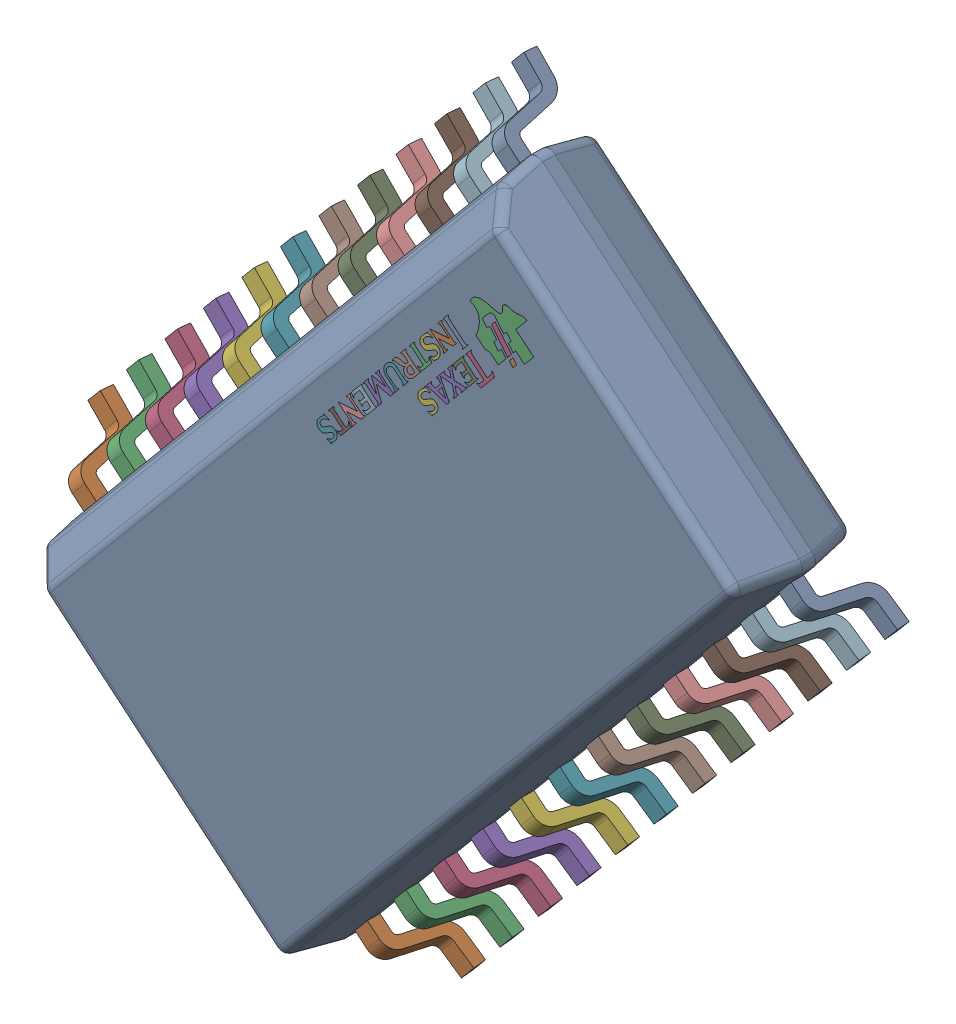
SolidWorks assembly U3, configuration Défaut. Lengths in mm.
Overall size (17.82 18.44 2.65).
28 component instances, 4 part files, 0 mates.
Components (placement in the parent):
- IC_Texas_Instruments_CD74HC4067M96_eec-1: IC_Texas_Instruments_CD74HC4067M96_eec [Défaut] at (-19.865 -20.828 0) x (-0.766044 0.642788 0) z (0 0 1) size (10.34 15.4 2.65)
  - BODY-SO-1: BODY-SO [Défaut] at (0 0 1.0825) x (0 1 0) z (1 0 0) size (15.4 2.45 7.5)
  - LEAD-SO-1: LEAD-SO [Défaut] at (4.315 6.985 0.25) x (0 1 0) z (1 0 0) size (0.41 1.43 1.42)
  - LEAD-SO-2: LEAD-SO [Défaut] at (4.315 5.715 0.25) x (0 1 0) z (1 0 0) size (0.41 1.43 1.42)
  - LEAD-SO-3: LEAD-SO [Défaut] at (4.315 4.445 0.25) x (0 1 0) z (1 0 0) size (0.41 1.43 1.42)
  - LEAD-SO-4: LEAD-SO [Défaut] at (4.315 3.175 0.25) x (0 1 0) z (1 0 0) size (0.41 1.43 1.42)
  - LEAD-SO-5: LEAD-SO [Défaut] at (4.315 1.905 0.25) x (0 1 0) z (1 0 0) size (0.41 1.43 1.42)
  - LEAD-SO-6: LEAD-SO [Défaut] at (4.315 0.635 0.25) x (0 1 0) z (1 0 0) size (0.41 1.43 1.42)
  - LEAD-SO-7: LEAD-SO [Défaut] at (4.315 -0.635 0.25) x (0 1 0) z (1 0 0) size (0.41 1.43 1.42)
  - LEAD-SO-8: LEAD-SO [Défaut] at (4.315 -1.905 0.25) x (0 1 0) z (1 0 0) size (0.41 1.43 1.42)
  - LEAD-SO-9: LEAD-SO [Défaut] at (4.315 -3.175 0.25) x (0 1 0) z (1 0 0) size (0.41 1.43 1.42)
  - LEAD-SO-10: LEAD-SO [Défaut] at (4.315 -4.445 0.25) x (0 1 0) z (1 0 0) size (0.41 1.43 1.42)
  - LEAD-SO-11: LEAD-SO [Défaut] at (4.315 -5.715 0.25) x (0 1 0) z (1 0 0) size (0.41 1.43 1.42)
  - LEAD-SO-12: LEAD-SO [Défaut] at (4.315 -6.985 0.25) x (0 1 0) z (1 0 0) size (0.41 1.43 1.42)
  - LEAD-SO-13: LEAD-SO [Défaut] at (-4.315 6.985 0.25) x (0 -1 0) z (-1 0 0) size (0.41 1.43 1.42)
  - LEAD-SO-14: LEAD-SO [Défaut] at (-4.315 5.715 0.25) x (0 -1 0) z (-1 0 0) size (0.41 1.43 1.42)
  - LEAD-SO-15: LEAD-SO [Défaut] at (-4.315 4.445 0.25) x (0 -1 0) z (-1 0 0) size (0.41 1.43 1.42)
  - LEAD-SO-16: LEAD-SO [Défaut] at (-4.315 3.175 0.25) x (0 -1 0) z (-1 0 0) size (0.41 1.43 1.42)
  - LEAD-SO-17: LEAD-SO [Défaut] at (-4.315 1.905 0.25) x (0 -1 0) z (-1 0 0) size (0.41 1.43 1.42)
  - LEAD-SO-18: LEAD-SO [Défaut] at (-4.315 0.635 0.25) x (0 -1 0) z (-1 0 0) size (0.41 1.43 1.42)
  - LEAD-SO-19: LEAD-SO [Défaut] at (-4.315 -0.635 0.25) x (0 -1 0) z (-1 0 0) size (0.41 1.43 1.42)
  - LEAD-SO-20: LEAD-SO [Défaut] at (-4.315 -1.905 0.25) x (0 -1 0) z (-1 0 0) size (0.41 1.43 1.42)
  - LEAD-SO-21: LEAD-SO [Défaut] at (-4.315 -3.175 0.25) x (0 -1 0) z (-1 0 0) size (0.41 1.43 1.42)
  - LEAD-SO-22: LEAD-SO [Défaut] at (-4.315 -4.445 0.25) x (0 -1 0) z (-1 0 0) size (0.41 1.43 1.42)
  - LEAD-SO-23: LEAD-SO [Défaut] at (-4.315 -5.715 0.25) x (0 -1 0) z (-1 0 0) size (0.41 1.43 1.42)
  - LEAD-SO-24: LEAD-SO [Défaut] at (-4.315 -6.985 0.25) x (0 -1 0) z (-1 0 0) size (0.41 1.43 1.42)
  - Texas Logo Yury-1: Texas Logo Yury [Défaut] at (2.174 -7.1221 2.551) x (0 1 0) z (0 0 1) size (1.32 1.29 0.11)
  - Texas Logo Yury - Copy-1: Texas Logo Yury - Copy [Défaut] at (2.0641 -7.1534 2.551) x (0 1 0) z (0 0 1) size (4.61 1.2 0.1)
